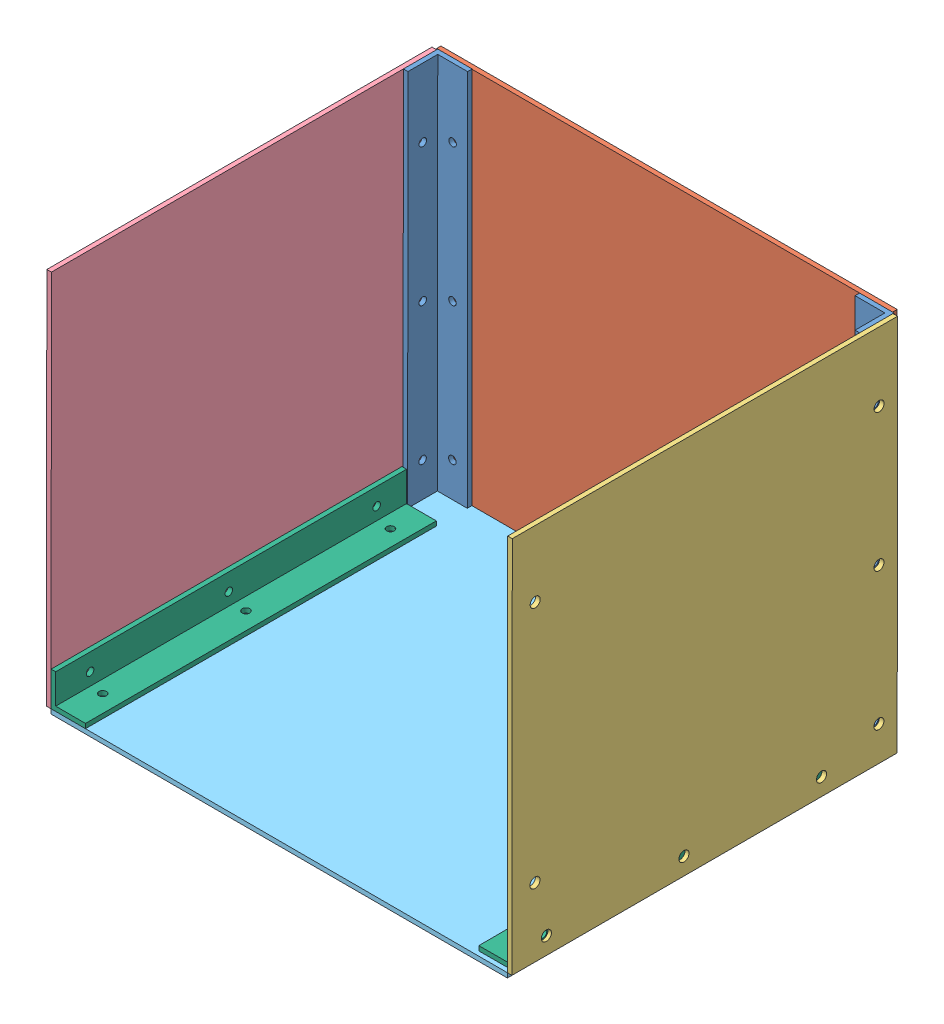
SolidWorks assembly 取り出し口, configuration ﾃﾞﾌｫﾙﾄ. Lengths in mm.
Overall size (203.14 167.17 170.53).
8 component instances, 6 part files, 25 mates.
Components (placement in the parent):
- 取り出し口 縦アングル-1: 取り出し口 縦アングル [ﾃﾞﾌｫﾙﾄ] at (-110.3389 102.9841 189.6987) x (1 -0.000849 0) z (-0.000849 -1 0) size (15 15 165)
- 取り出し口板 奥面-1: 取り出し口板 奥面 [ﾃﾞﾌｫﾙﾄ] at (-11.4536 35.3224 187.6987) size (199 165 2)
- 取り出し口 縦アングル-2: 取り出し口 縦アングル [ﾃﾞﾌｫﾙﾄ] at (88.661 102.8151 189.6987) x (0 0 1) z (-0.000849 -1 0) size (15 15 165)
- 取り出し口板 右面-1: 取り出し口板 右面 [ﾃﾞﾌｫﾙﾄ] at (88.6045 36.3152 274.1987) x (0 0 -1) z (1 -0.000849 0) size (168 165 2)
- 取り出し口板 左面-2: 取り出し口板 左面 [ﾃﾞﾌｫﾙﾄ] at (-112.3954 36.4858 274.1987) x (0 0 -1) z (1 -0.000849 0) size (168 165 2)
- 取り出し口板 下面-1: 取り出し口板 下面 [ﾃﾞﾌｫﾙﾄ] at (-10.968 -49.1003 273.1987) x (1 -0.000849 0) z (0.000849 1 0) size (199 170 2)
- 取り出し口 横アングル-1: 取り出し口 横アングル [ﾃﾞﾌｫﾙﾄ] at (-110.4663 -47.0158 203.1987) x (1 -0.000849 0) z (0 0 1) size (15 15 155)
- 取り出し口 横アングル-2: 取り出し口 横アングル [ﾃﾞﾌｫﾙﾄ] at (89.0936 -47.1853 358.1666) x (-0.999992 0.000849 0.004) z (-0.004 0.000003 -0.999992) size (15 15 155)
Mates (geometry in assembly coordinates):
- 同心円1: concentric: cylinder of 取り出し口 縦アングル-1 through (-102.9536 87.8224 204.6987) axis (0 0 -1) radius 2.2; cylinder of 取り出し口板 奥面-1 through (-102.9536 87.8224 187.6987) axis (0 0 1) radius 2.2
- 同心円2: concentric: cylinder of 取り出し口 縦アングル-1 through (-102.9536 27.8224 204.6987) axis (0 0 -1) radius 2.2; cylinder of 取り出し口板 奥面-1 through (-102.9536 27.8224 187.6987) axis (0 0 1) radius 2.2
- 同心円3: concentric: cylinder of 取り出し口 縦アングル-1 through (-102.9536 -32.1776 204.6987) axis (0 0 -1) radius 2.2; cylinder of 取り出し口板 奥面-1 through (-102.9536 -32.1776 187.6987) axis (0 0 1) radius 2.2
- 一致1: coincident: plane of 取り出し口 縦アングル-1 through (-95.4663 -47.0286 189.6987) normal (0 0 -1); plane of 取り出し口板 奥面-1 through (-11.4536 35.3224 189.6987) normal (0 0 1)
- 同心円4: concentric: cylinder of 取り出し口板 奥面-1 through (80.0464 87.8224 187.6987) axis (0 0 1) radius 2.2; cylinder of 取り出し口 縦アングル-2 through (80.0464 87.8224 204.6987) axis (0 0 -1) radius 2.2
- 同心円5: concentric: cylinder of 取り出し口板 奥面-1 through (80.0464 -32.1776 187.6987) axis (0 0 1) radius 2.2; cylinder of 取り出し口 縦アングル-2 through (80.0464 -32.1776 204.6987) axis (0 0 -1) radius 2.2
- 一致2: coincident: plane of 取り出し口板 奥面-1 through (-11.4536 35.3224 189.6987) normal (0 0 1); plane of 取り出し口 縦アングル-2 through (88.5336 -47.1848 189.6987) normal (0 0 -1)
- 同心円6: concentric: cylinder of 取り出し口 縦アングル-2 through (73.0464 87.8224 197.6987) axis (1 0 0) radius 2.2; cylinder of 取り出し口板 右面-1 through (88.0464 87.8224 197.6987) axis (1 0 0) radius 2.2
- 同心円7: concentric: cylinder of 取り出し口 縦アングル-2 through (73.0464 -32.1776 197.6987) axis (1 0 0) radius 2.2; cylinder of 取り出し口板 右面-1 through (88.0464 -32.1776 197.6987) axis (1 0 0) radius 2.2
- 一致3: coincident: plane of 取り出し口 縦アングル-2 through (88.5336 -47.1848 204.6987) normal (1 -0.000849 0); plane of 取り出し口板 右面-1 through (88.6045 36.3152 274.1987) normal (-1 0.000849 0)
- 同心円8: concentric: cylinder of 取り出し口 縦アングル-1 through (-95.9536 87.8224 197.6987) axis (-1 0 0) radius 2.2; cylinder of 取り出し口板 左面-2 through (-112.9536 87.8224 197.6987) axis (1 0 0) radius 2.2
- 同心円9: concentric: cylinder of 取り出し口 縦アングル-1 through (-95.9536 -32.1776 197.6987) axis (-1 0 0) radius 2.2; cylinder of 取り出し口板 左面-2 through (-112.9536 -32.1776 197.6987) axis (1 0 0) radius 2.2
- 一致4: coincident: plane of 取り出し口 縦アングル-1 through (-110.4663 -47.0158 189.6987) normal (-1 0.000849 0); plane of 取り出し口板 左面-2 through (-110.3954 36.4841 274.1987) normal (1 -0.000849 0)
- 一致6: coincident: line of 取り出し口板 左面-2 through (-110.4663 -47.0158 358.1987) axis (0 0 -1); line of 取り出し口板 下面-1 through (-110.4663 -47.0158 188.1987) axis (0 0 1)
- 一致7: coincident: line of 取り出し口板 右面-1 through (88.5336 -47.1848 358.1987) axis (0 0 -1); line of 取り出し口板 下面-1 through (88.5336 -47.1848 358.1987) axis (0 0 -1)
- 同心円10: concentric: cylinder of 取り出し口板 下面-1 through (-102.9536 -49.1776 217.6987) axis (0 1 0) radius 2.2; cylinder of 取り出し口 横アングル-1 through (-102.9536 -201.1776 217.6987) axis (0 1 0) radius 2.2
- 同心円11: concentric: cylinder of 取り出し口板 左面-2 through (-112.9536 -39.6776 342.6987) axis (1 0 0) radius 2.2; cylinder of 取り出し口 横アングル-1 through (-264.9536 -39.6776 342.6987) axis (1 0 0) radius 2.2
- 同心円12: concentric: cylinder of 取り出し口板 下面-1 through (81.0319 -49.1784 218.1987) axis (0.000849 1 0) radius 2.2; cylinder of 取り出し口 横アングル-2 through (81.0353 -45.1784 218.1977) axis (0.000849 1 0) radius 1.65
- 同心円13: concentric: circle of 取り出し口板 下面-1; cylinder of 取り出し口 横アングル-2 through (81.0353 -45.1784 343.1987) axis (0.000849 1 0) radius 1.65
- 一致8: coincident: plane of 取り出し口板 下面-1 through (-10.9663 -47.1003 273.1987) normal (0.000849 1 0); plane of 取り出し口 横アングル-2 through (73.4737 -47.172 203.2278) normal (-0.000849 -1 0)
- 同心円14: concentric: cylinder of 取り出し口板 左面-2 through (-112.4599 -39.5141 343.1987) axis (1 -0.000849 0) radius 2.2; cylinder of 取り出し口 横アングル-1 through (-108.4599 -39.5175 343.1987) axis (1 -0.000849 0) radius 1.65
- 同心円15: concentric: cylinder of 取り出し口板 下面-1 through (-102.968 -49.0222 343.1987) axis (0.000849 1 0) radius 2.2; circle of 取り出し口 横アングル-1
- 同心円16: concentric: cylinder of 取り出し口 縦アングル-2 through (86.5464 -32.1831 198.1987) axis (-1 0.000849 0) radius 1.65; cylinder of 取り出し口板 右面-1 through (88.5464 -32.1848 198.1987) axis (1 -0.000849 0) radius 2.2
- 同心円17: concentric: cylinder of 取り出し口板 奥面-1 through (80.0464 -32.1776 187.6987) axis (0 0 1) radius 2.2; cylinder of 取り出し口 縦アングル-2 through (80.0464 -32.1776 191.6987) axis (0 0 1) radius 1.65
- 同心円18: concentric: cylinder of 取り出し口 縦アングル-1 through (-108.4536 -32.0175 198.1987) axis (1 -0.000849 0) radius 1.65; cylinder of 取り出し口板 左面-2 through (-112.4536 -32.0141 198.1987) axis (1 -0.000849 0) radius 2.2
